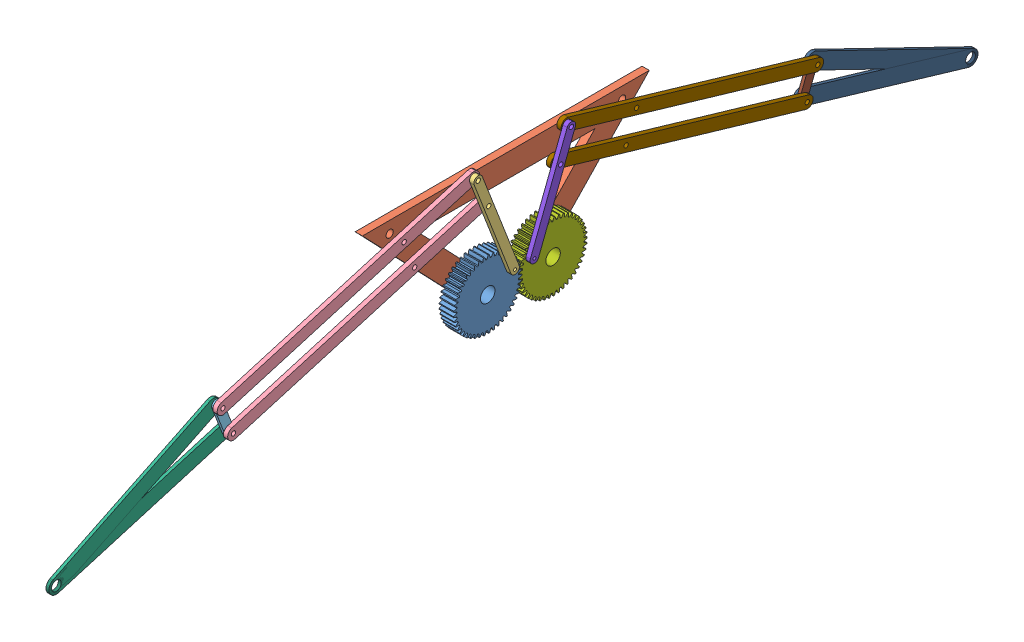
SolidWorks assembly assembly of us, configuration Default. Lengths in mm.
Overall size (18 115.72 647.82).
16 component instances, 12 part files, 67 mates.
Components (placement in the parent):
- Part2^assembly of us-1: Part2^assembly of us [Default] at (0 0 22.5) x (0 -0.879771 -0.475398) z (1 0 0) size (46.99 46.96 10) (virtual)
- Part3^assembly of us-1: Part3^assembly of us [Default] at (-5 0.0991 0) x (0 0 -1) z (1 0 0) size (197.45 76.1 5) (virtual)
- Part4^assembly of us-1: Part4^assembly of us [Default] at (10 58.8604 -19.1894) x (-1 0 0) z (0 0.169863 0.985468) size (3 66.39 42.15) (virtual)
- Part5^assembly of us-1: Part5^assembly of us [Default] at (7 74.2099 32.0324) x (0 0.282215 -0.959351) z (1 0 0) size (188 8 3) (virtual)
- Part5^assembly of us-2: Part5^assembly of us [Default] at (7 55.4519 24.7844) x (0 0.281629 -0.959523) z (1 0 0) size (188 8 3) (virtual)
- Part6^assembly of us-1: Part6^assembly of us [Default] at (5.2165 23.4111 204.7157) x (0 0.360855 -0.932622) z (1 0 0) size (6 26 2) (virtual)
- Part7^assembly of us-1: Part7^assembly of us [Default] at (5.2165 50.189 31.4668) x (0 -0.230452 0.973084) z (-1 0 0) size (130.26 16.93 2) (virtual)
- Part7^assembly of us-2: Part7^assembly of us [Default] at (5.2165 95.3318 48.3255) x (0 -0.386188 0.92242) z (-1 0 0) size (130.26 16.93 2) (virtual)
- Part8^assembly of us-1: Part8^assembly of us [Default] at (10 0 0) x (0 0 -1) z (1 0 0) (virtual)
- Part9^assembly of us-1: Part9^assembly of us [Default] at (0 32.5976 -11.2745) x (0 0.28539 -0.958412) z (1 0 0) size (46.98 46.98 10) (virtual)
- MirrorPart4^assembly of us-5: MirrorPart4^assembly of us [Default] at (10 58.8604 19.1894) x (-1 0 0) z (0 -0.169863 0.985468) size (3 66.39 42.15) (virtual)
- MirrorPart5^assembly of us-11: MirrorPart5^assembly of us [Default] at (7 55.4519 -24.7844) x (0 0.281629 0.959523) z (-1 0 0) size (188 8 3) (virtual)
- MirrorPart5^assembly of us-12: MirrorPart5^assembly of us [Default] at (7 74.2099 -32.0324) x (0 0.282215 0.959351) z (-1 0 0) size (188 8 3) (virtual)
- MirrorPart7^assembly of us-11: MirrorPart7^assembly of us [Default] at (5.2165 50.189 -31.4668) x (0 -0.230452 -0.973084) z (1 0 0) size (130.26 16.93 2) (virtual)
- MirrorPart7^assembly of us-12: MirrorPart7^assembly of us [Default] at (5.2165 95.3318 -48.3255) x (0 -0.386188 -0.92242) z (1 0 0) size (130.26 16.93 2) (virtual)
- MirrorPart6^assembly of us-6: MirrorPart6^assembly of us [Default] at (5.2165 23.4111 -204.7157) x (0 0.360855 0.932622) z (-1 0 0) size (6 26 2) (virtual)
Mates (geometry in assembly coordinates):
- Concentric1: concentric: cylinder of Part2^assembly of us-1 through (0 0 22.5) axis (1 0 0) radius 5
- Coincident5: coincident anti-aligned: plane of Part2^assembly of us-1 through (0 4.4102 12.8827) normal (-1 0 0)
- Coincident6: coincident anti-aligned: plane of Part2^assembly of us-1 through (0 4.4102 12.8827) normal (-1 0 0); plane of Part3^assembly of us-1 through (0 -0.0001 -22.4996) normal (1 0 0)
- Concentric4: concentric anti-aligned: cylinder of Part2^assembly of us-1 through (0 0 22.5) axis (1 0 0) radius 5; cylinder of Part3^assembly of us-1 through (0 0 22.5) axis (-1 0 0) radius 5
- Concentric6: concentric anti-aligned: cylinder of Part2^assembly of us-1 through (0 -10.9748 8.2328) axis (1 0 0) radius 1; cylinder of Part4^assembly of us-1 through (13 -10.9748 8.2328) axis (-1 0 0) radius 1
- Coincident7: coincident anti-aligned: plane of Part2^assembly of us-1 through (10 4.4102 12.8827) normal (1 0 0); plane of Part4^assembly of us-1 through (10 -10.9748 8.2328) normal (-1 0 0)
- Concentric7: concentric aligned: cylinder of Part4^assembly of us-1 through (13 55.9005 30.1765) axis (-1 0 0) radius 1.5; cylinder of Part5^assembly of us-1 through (10 55.9005 30.1765) axis (-1 0 0) radius 1.5
- Concentric8: concentric aligned: cylinder of Part3^assembly of us-1 through (0 60.0993 80.0001) axis (-1 0 0) radius 2.5; cylinder of Part5^assembly of us-1 through (10 60.0991 79.9999) axis (-1 0 0) radius 1.5
- Concentric9: concentric aligned: cylinder of Part4^assembly of us-1 through (13 36.7933 23.9068) axis (-1 0 0) radius 1.5; cylinder of Part5^assembly of us-2 through (10 36.7933 23.9068) axis (-1 0 0) radius 1.5
- Coincident8: coincident anti-aligned: plane of Part4^assembly of us-1 through (10 -10.9748 8.2328) normal (-1 0 0); plane of Part5^assembly of us-2 through (10 36.7933 23.9068) normal (1 0 0)
- Concentric10: concentric aligned: cylinder of Part4^assembly of us-1 through (13 55.9005 30.1765) axis (-1 0 0) radius 1.5; cylinder of Part5^assembly of us-1 through (10 55.9005 30.1765) axis (-1 0 0) radius 1.5
- Concentric11: concentric aligned: cylinder of Part5^assembly of us-1 through (10 71.0156 209.5407) axis (-1 0 0) radius 1.5; cylinder of Part6^assembly of us-1 through (7.2165 71.0156 209.5407) axis (-1 0 0) radius 1.5
- Concentric12: concentric aligned: cylinder of Part5^assembly of us-2 through (10 52.027 203.261) axis (-1 0 0) radius 1.5; cylinder of Part6^assembly of us-1 through (7.2165 52.027 203.261) axis (-1 0 0) radius 1.5
- Coincident9: coincident anti-aligned: plane of Part4^assembly of us-1 through (10 -10.9748 8.2328) normal (-1 0 0); plane of Part5^assembly of us-1 through (10 55.9005 30.1765) normal (1 0 0)
- Concentric15: concentric anti-aligned: cylinder of Part6^assembly of us-1 through (7.2165 71.0156 209.5407) axis (-1 0 0) radius 1.5; cylinder of Part7^assembly of us-2 through (3.2165 71.0156 209.5407) axis (1 0 0) radius 1.5
- Concentric16: concentric anti-aligned: cylinder of Part6^assembly of us-1 through (7.2165 52.027 203.261) axis (-1 0 0) radius 1.5; cylinder of Part7^assembly of us-1 through (3.2165 52.027 203.261) axis (1 0 0) radius 1.5
- Coincident10: coincident anti-aligned: plane of Part6^assembly of us-1 through (5.2165 71.0156 209.5407) normal (-1 0 0); plane of Part7^assembly of us-2 through (5.2165 70.3562 211.3659) normal (1 0 0)
- Coincident11: coincident anti-aligned: plane of Part6^assembly of us-1 through (5.2165 71.0156 209.5407) normal (-1 0 0); plane of Part7^assembly of us-1 through (5.2165 51.6744 205.1694) normal (1 0 0)
- Concentric17: concentric aligned: cylinder of Part7^assembly of us-1 through (3.2165 23.3055 321.9587) axis (1 0 0) radius 3.3572; cylinder of Part7^assembly of us-2 through (3.2165 23.3055 321.9587) axis (1 0 0) radius 3.3572
- Parallel5: parallel aligned: plane of Part2^Assem1-3 through (14 -0.5332 -85.904) normal (1 0 0); plane of Part2^Assem1-4 through (14 -0.5332 -40.9044) normal (1 0 0)
- Coincident18: coincident aligned: plane of Part2^Assem1-3 through (14 -0.5332 -85.904) normal (1 0 0); plane of Part2^Assem1-4 through (14 -0.5332 -40.9044) normal (1 0 0)
- GearMate3: gear = 10 : 10 mm: cylinder of Part2^Assem1-4 through (4 -10.1408 -36.4733) axis (1 0 0) radius 5; cylinder of Part2^Assem1-3 through (4 -10.1408 -81.4728) axis (1 0 0) radius 5
- Concentric18: concentric aligned: cylinder of Part7^Assem1-3 through (7 -20.6429 259.4258) axis (1 0 0) radius 3.3572; cylinder of Part7^Assem1-4 through (7 -20.6429 259.4258) axis (1 0 0) radius 3.3572
- Concentric19: concentric anti-aligned: cylinder of Part2^Assem1-3 through (4 -10.1408 -81.4728) axis (1 0 0) radius 5; cylinder of Part3^Assem1-2 through (4 -10.1408 -81.4728) axis (-1 0 0) radius 5
- Coincident19: coincident anti-aligned: plane of Part2^Assem1-4 through (4 -0.5332 -40.9044) normal (-1 0 0); plane of Part3^Assem1-2 through (4 -10.1408 -81.4728) normal (1 0 0)
- Concentric20: concentric anti-aligned: cylinder of Part2^Assem1-4 through (4 -10.1408 -36.4733) axis (1 0 0) radius 5; cylinder of Part3^Assem1-2 through (4 -10.1408 -36.4733) axis (-1 0 0) radius 5
- Concentric21: concentric anti-aligned: cylinder of Part4^Assem1-2 through (17 -9.1873 -54.448) axis (-1 0 0) radius 1; cylinder of Part2^Assem1-4 through (4 -9.1873 -54.448) axis (1 0 0) radius 1
- Coincident20: coincident anti-aligned: plane of Part4^Assem1-2 through (14 -9.1873 -54.448) normal (-1 0 0); plane of Part2^Assem1-4 through (14 -0.5332 -40.9044) normal (1 0 0)
- Concentric22: concentric aligned: cylinder of Part5^Assem1-4 through (14 49.9584 21.0269) axis (-1 0 0) radius 1.5; cylinder of Part3^Assem1-2 through (4 49.9584 21.0269) axis (-1 0 0) radius 2.5
- Concentric23: concentric aligned: cylinder of Part5^Assem1-4 through (14 56.2676 -28.5734) axis (-1 0 0) radius 1.5; cylinder of Part4^Assem1-2 through (17 56.2676 -28.5734) axis (-1 0 0) radius 1.5
- Coincident21: coincident anti-aligned: plane of Part5^Assem1-3 through (14 37.5662 -35.9661) normal (1 0 0); plane of Part4^Assem1-2 through (14 -9.1873 -54.448) normal (-1 0 0)
- Concentric24: concentric aligned: cylinder of Part5^Assem1-3 through (14 37.5662 -35.9661) axis (-1 0 0) radius 1.5; cylinder of Part4^Assem1-2 through (17 37.5662 -35.9661) axis (-1 0 0) radius 1.5
- Concentric25: concentric aligned: cylinder of Part5^Assem1-4 through (14 56.2676 -28.5734) axis (-1 0 0) radius 1.5; cylinder of Part4^Assem1-2 through (17 56.2676 -28.5734) axis (-1 0 0) radius 1.5
- Concentric26: concentric aligned: cylinder of Part6^Assem1-2 through (11 14.9655 142.6094) axis (-1 0 0) radius 1.5; cylinder of Part5^Assem1-3 through (14 14.9655 142.6094) axis (-1 0 0) radius 1.5
- Concentric27: concentric aligned: cylinder of Part6^Assem1-2 through (11 33.5547 149.9879) axis (-1 0 0) radius 1.5; cylinder of Part5^Assem1-4 through (14 33.5547 149.9879) axis (-1 0 0) radius 1.5
- Coincident22: coincident anti-aligned: plane of Part5^Assem1-4 through (14 56.2676 -28.5734) normal (1 0 0); plane of Part4^Assem1-2 through (14 -9.1873 -54.448) normal (-1 0 0)
- Concentric28: concentric anti-aligned: cylinder of Part6^Assem1-2 through (11 14.9655 142.6094) axis (-1 0 0) radius 1.5; cylinder of Part7^Assem1-4 through (7 14.9655 142.6094) axis (1 0 0) radius 1.5
- Coincident23: coincident anti-aligned: plane of Part7^Assem1-3 through (9 32.7897 151.7714) normal (1 0 0); plane of Part6^Assem1-2 through (9 33.5547 149.9879) normal (-1 0 0)
- Concentric29: concentric anti-aligned: cylinder of Part7^Assem1-3 through (7 33.5547 149.9879) axis (1 0 0) radius 1.5; cylinder of Part6^Assem1-2 through (11 33.5547 149.9879) axis (-1 0 0) radius 1.5
- Coincident24: coincident anti-aligned: plane of Part6^Assem1-2 through (9 33.5547 149.9879) normal (-1 0 0); plane of Part7^Assem1-4 through (9 14.5019 144.4938) normal (1 0 0)
- Parallel6: parallel aligned: plane of Part2^Assem1-5 through (14 -13.7727 41.2966) normal (1 0 0); plane of Part2^Assem1-6 through (14 -13.7727 86.2961) normal (1 0 0)
- Coincident25: coincident aligned: plane of Part2^Assem1-5 through (14 -13.7727 41.2966) normal (1 0 0); plane of Part2^Assem1-6 through (14 -13.7727 86.2961) normal (1 0 0)
- GearMate4: gear = 10 : 10 mm: cylinder of Part2^Assem1-6 through (4 -23.3804 90.7273) axis (1 0 0) radius 5; cylinder of Part2^Assem1-5 through (4 -23.3804 45.7278) axis (1 0 0) radius 5
- Concentric30: concentric aligned: cylinder of Part7^Assem1-5 through (7 -33.8825 386.6264) axis (1 0 0) radius 3.3572; cylinder of Part7^Assem1-6 through (7 -33.8825 386.6264) axis (1 0 0) radius 3.3572
- Concentric31: concentric anti-aligned: cylinder of Part2^Assem1-5 through (4 -23.3804 45.7278) axis (1 0 0) radius 5; cylinder of Part3^Assem1-3 through (4 -23.3804 45.7278) axis (-1 0 0) radius 5
- Coincident26: coincident anti-aligned: plane of Part2^Assem1-6 through (4 -13.7727 86.2961) normal (-1 0 0); plane of Part3^Assem1-3 through (4 -23.3804 45.7278) normal (1 0 0)
- Concentric32: concentric anti-aligned: cylinder of Part2^Assem1-6 through (4 -23.3804 90.7273) axis (1 0 0) radius 5; cylinder of Part3^Assem1-3 through (4 -23.3804 90.7273) axis (-1 0 0) radius 5
- Concentric33: concentric anti-aligned: cylinder of Part4^Assem1-3 through (17 -22.4268 72.7526) axis (-1 0 0) radius 1; cylinder of Part2^Assem1-6 through (4 -22.4268 72.7526) axis (1 0 0) radius 1
- Coincident27: coincident anti-aligned: plane of Part4^Assem1-3 through (14 -22.4268 72.7526) normal (-1 0 0); plane of Part2^Assem1-6 through (14 -13.7727 86.2961) normal (1 0 0)
- Concentric34: concentric aligned: cylinder of Part5^Assem1-6 through (14 36.7189 148.2275) axis (-1 0 0) radius 1.5; cylinder of Part3^Assem1-3 through (4 36.7189 148.2275) axis (-1 0 0) radius 2.5
- Concentric35: concentric aligned: cylinder of Part5^Assem1-6 through (14 43.028 98.6272) axis (-1 0 0) radius 1.5; cylinder of Part4^Assem1-3 through (17 43.028 98.6272) axis (-1 0 0) radius 1.5
- Coincident28: coincident anti-aligned: plane of Part5^Assem1-5 through (14 24.3266 91.2344) normal (1 0 0); plane of Part4^Assem1-3 through (14 -22.4268 72.7526) normal (-1 0 0)
- Concentric36: concentric aligned: cylinder of Part5^Assem1-5 through (14 24.3266 91.2344) axis (-1 0 0) radius 1.5; cylinder of Part4^Assem1-3 through (17 24.3266 91.2344) axis (-1 0 0) radius 1.5
- Concentric37: concentric aligned: cylinder of Part5^Assem1-6 through (14 43.028 98.6272) axis (-1 0 0) radius 1.5; cylinder of Part4^Assem1-3 through (17 43.028 98.6272) axis (-1 0 0) radius 1.5
- Concentric38: concentric aligned: cylinder of Part6^Assem1-3 through (11 1.7259 269.8099) axis (-1 0 0) radius 1.5; cylinder of Part5^Assem1-5 through (14 1.7259 269.8099) axis (-1 0 0) radius 1.5
- Concentric39: concentric aligned: cylinder of Part6^Assem1-3 through (11 20.3151 277.1884) axis (-1 0 0) radius 1.5; cylinder of Part5^Assem1-6 through (14 20.3151 277.1884) axis (-1 0 0) radius 1.5
- Coincident29: coincident anti-aligned: plane of Part5^Assem1-6 through (14 43.028 98.6272) normal (1 0 0); plane of Part4^Assem1-3 through (14 -22.4268 72.7526) normal (-1 0 0)
- Concentric40: concentric anti-aligned: cylinder of Part6^Assem1-3 through (11 1.7259 269.8099) axis (-1 0 0) radius 1.5; cylinder of Part7^Assem1-6 through (7 1.7259 269.8099) axis (1 0 0) radius 1.5
- Coincident30: coincident anti-aligned: plane of Part7^Assem1-5 through (9 19.5502 278.972) normal (1 0 0); plane of Part6^Assem1-3 through (9 20.3151 277.1884) normal (-1 0 0)
- Concentric41: concentric anti-aligned: cylinder of Part7^Assem1-5 through (7 20.3151 277.1884) axis (1 0 0) radius 1.5; cylinder of Part6^Assem1-3 through (11 20.3151 277.1884) axis (-1 0 0) radius 1.5
- Coincident31: coincident anti-aligned: plane of Part6^Assem1-3 through (9 20.3151 277.1884) normal (-1 0 0); plane of Part7^Assem1-6 through (9 1.2624 271.6944) normal (1 0 0)
- Concentric75: concentric anti-aligned: cylinder of Part3^assembly of us-1 through (0 -0.0001 -22.4996) axis (-1 0 0) radius 5; cylinder of Part9^assembly of us-1 through (0 -0.0001 -22.4996) axis (1 0 0) radius 5
- Coincident40: coincident aligned: plane of Part3^assembly of us-1 through (0 -0.0001 -22.4996) normal (1 0 0)
- GearMate10: gear = 10 : 10 mm: cylinder of Part2^assembly of us-1 through (0 0 22.5) axis (1 0 0) radius 5; cylinder of Part9^assembly of us-1 through (0 -0.0001 -22.4996) axis (1 0 0) radius 5
- Coincident41: coincident anti-aligned: plane of Part3^assembly of us-1 through (0 -0.0001 -22.4996) normal (1 0 0); plane of Part9^assembly of us-1 through (0 2.3312 -12.1883) normal (-1 0 0)
- Coincident42: coincident anti-aligned: plane of Part2^assembly of us-1 through (0 4.4102 12.8827) normal (-1 0 0); plane of Part3^assembly of us-1 through (0 -0.0001 -22.4996) normal (1 0 0)
- Concentric81: concentric aligned: cylinder of Part3^assembly of us-1 through (0 60.0991 -79.9999) axis (-1 0 0) radius 2.5; cylinder of MirrorPart5^assembly of us-12 through (10 60.0991 -79.9999) axis (-1 0 0) radius 1.5
